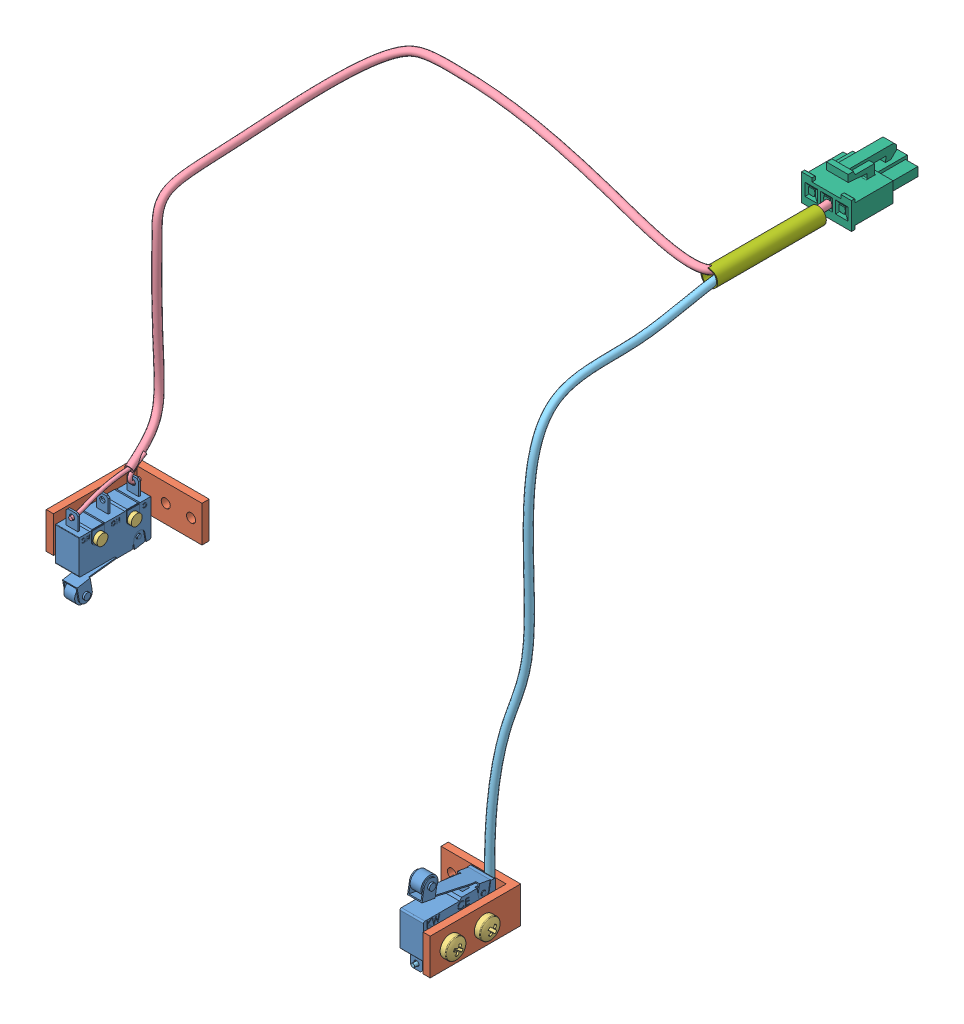
SolidWorks assembly SensorsAssembly, configuration Default. Lengths in mm.
Overall size (110.85 138.03 134.43).
14 component instances, 7 part files, 0 mates.
Components (placement in the parent):
- EndSensorModule-1: EndSensorModule [End Sensor Module] at (0.6758 0.3516 15.9754) size (22.35 22.49 25)
  - Limit Switch-1: Limit Switch [Default] at (50.1242 56.8994 -5.2001) x (0 -0.000062 1) z (-1 0 0) size (19.88 22.49 6.9)
  - SensorMount-1: SensorMount [Default] at (52.3242 49.1484 -9.9754) x (-1 0 0) z (0 1 0) size (20 25 10)
  - pan head cross recess screw_din-1: pan head cross recess screw_din [DIN EN ISO 7045 - M3 x 10 - Z - 10N] at (54.7242 49.1484 9.4746) x (-1 0 0) z (0 0.445535 0.895265) size (12.35 5.6 5.6)
  - pan head cross recess screw_din-2: pan head cross recess screw_din [DIN EN ISO 7045 - M3 x 10 - Z - 10N] at (54.7242 49.1484 0.0246) x (-1 0 0) z (0 0.679498 0.733678) size (12.35 5.6 5.6)
- EndSensorModule-2: EndSensorModule [End Sensor Module] at (-0.6758 147.6484 15.9754) x (-1 0 0) z (0 0 1) size (22.35 22.49 25)
  - Limit Switch-1: Limit Switch [Default] at (50.1242 56.8994 -5.2001) x (0 -0.000062 1) z (-1 0 0) size (19.88 22.49 6.9)
  - SensorMount-1: SensorMount [Default] at (52.3242 49.1484 -9.9754) x (-1 0 0) z (0 1 0) size (20 25 10)
  - pan head cross recess screw_din-1: pan head cross recess screw_din [DIN EN ISO 7045 - M3 x 10 - Z - 10N] at (54.7242 49.1484 9.4746) x (-1 0 0) z (0 0.445535 0.895265) size (12.35 5.6 5.6)
  - pan head cross recess screw_din-2: pan head cross recess screw_din [DIN EN ISO 7045 - M3 x 10 - Z - 10N] at (54.7242 49.1484 0.0246) x (-1 0 0) z (0 0.679498 0.733678) size (12.35 5.6 5.6)
- CableTopEndSensor^SensorsAssembly-1: CableTopEndSensor^SensorsAssembly [Cable Top End Sensor] at (-47.5515 103.4682 9.2244) x (0 -1 0) z (-1 0 0) size (70.83 114.96 104.45) (virtual)
- CableBottomEndSensor^SensorsAssembly-1: CableBottomEndSensor^SensorsAssembly [Cable Bottom End Sensor] at (47.5296 44.4259 9.8033) x (0 1 0) z (1 0 0) size (131.65 95.88 6.96) (virtual)
- 3 CIRCUIT RECEPTACLE MOLEX-1: 3 CIRCUIT RECEPTACLE MOLEX [Default] at (48.5924 171.0009 -94.3283) x (-1 0 0) z (0 0 -1) size (13.8 10.2 20.6)
- Heat-Shrink Tube^SensorsAssembly-1: Heat-Shrink Tube^SensorsAssembly [Heat shrink tube] at (49.2843 169.6081 -79.7864) size (4.6 4.6 30) (virtual)
